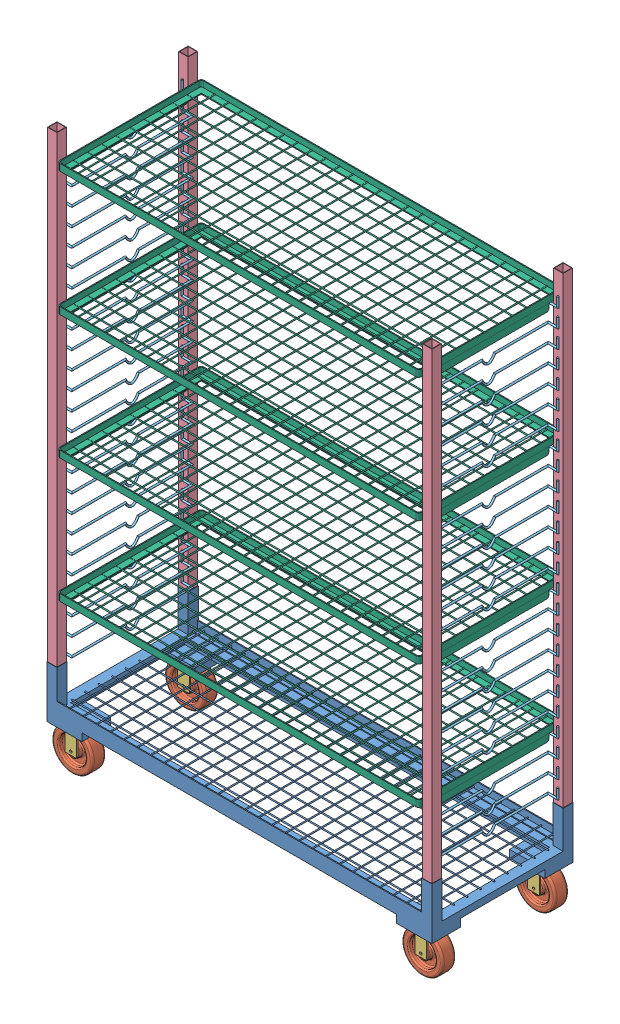
SolidWorks assembly cart_assembly, configuration Default. Lengths in mm.
Overall size (1465.58 2082.8 540.51).
71 component instances, 6 part files, 15 mates.
Components (placement in the parent):
- base-1: base [Default] at (534.0064 765.885 1057.2347) size (1444.62 194.06 530.22)
- wheel_assembly-1: wheel_assembly [Default] at (8.6921 764.7646 844.3099) x (0 0 -1) z (-1 0 0) size (99.57 177.8 152.4)
  - wheel-1: wheel [Default] at (-26.5523 104.0356 130.9582) size (50.8 152.4 152.4)
  - wheel_housing-1: wheel_housing [Default] at (48.6317 2.4356 193.4422) x (0 1 0) z (0 0 1) size (114.3 99.57 124.97)
- wheel_assembly-2: wheel_assembly [Default] at (1321.8721 764.7646 844.3099) x (0 0 -1) z (-1 0 0) size (99.57 177.8 152.4)
  - wheel-1: wheel [Default] at (-26.5523 104.0356 130.9582) size (50.8 152.4 152.4)
  - wheel_housing-1: wheel_housing [Default] at (48.6317 2.4356 193.4422) x (0 1 0) z (0 0 1) size (114.3 99.57 124.97)
- wheel_assembly-3: wheel_assembly [Default] at (8.6921 764.7646 1267.2199) x (0 0 -1) z (-1 0 0) size (99.57 177.8 152.4)
  - wheel-1: wheel [Default] at (-26.5523 104.0356 130.9582) size (50.8 152.4 152.4)
  - wheel_housing-1: wheel_housing [Default] at (48.6317 2.4356 193.4422) x (0 1 0) z (0 0 1) size (114.3 99.57 124.97)
- wheel_assembly-4: wheel_assembly [Default] at (1321.8721 764.7646 1267.2199) x (0 0 -1) z (-1 0 0) size (99.57 177.8 152.4)
  - wheel-1: wheel [Default] at (-26.5523 104.0356 130.9582) size (50.8 152.4 152.4)
  - wheel_housing-1: wheel_housing [Default] at (48.6317 2.4356 193.4422) x (0 1 0) z (0 0 1) size (114.3 99.57 124.97)
- side_assembly-1: side_assembly [Default] at (3135.9189 1569.601 1280.3971) x (0 0 1) z (-1 0 0) size (527.68 1898.65 55.7)
  - side-1: side [Default] at (-485.354 -800.922 1914.779) size (527.68 1898.65 35.56)
  - cross_bar-2: cross_bar [Default] at (-448.2065 -580.3312 1897.771) size (456.56 60.39 42.04)
  - cross_bar-3: cross_bar [Default] at (-448.2065 -513.7832 1897.771) size (456.56 60.39 42.04)
  - cross_bar-4: cross_bar [Default] at (-448.2065 -447.2352 1897.771) size (456.56 60.39 42.04)
  - cross_bar-5: cross_bar [Default] at (-448.2065 -380.6872 1897.771) size (456.56 60.39 42.04)
  - cross_bar-6: cross_bar [Default] at (-448.2065 -314.1392 1897.771) size (456.56 60.39 42.04)
  - cross_bar-7: cross_bar [Default] at (-448.2065 -247.5912 1897.771) size (456.56 60.39 42.04)
  - cross_bar-8: cross_bar [Default] at (-448.2065 -181.0432 1897.771) size (456.56 60.39 42.04)
  - cross_bar-9: cross_bar [Default] at (-448.2065 -114.4952 1897.771) size (456.56 60.39 42.04)
  - cross_bar-10: cross_bar [Default] at (-448.2065 -47.9472 1897.771) size (456.56 60.39 42.04)
  - cross_bar-11: cross_bar [Default] at (-448.2065 18.6008 1897.771) size (456.56 60.39 42.04)
  - cross_bar-12: cross_bar [Default] at (-448.2065 85.1488 1897.771) size (456.56 60.39 42.04)
  - cross_bar-13: cross_bar [Default] at (-448.2065 151.6968 1897.771) size (456.56 60.39 42.04)
  - cross_bar-14: cross_bar [Default] at (-448.2065 218.2448 1897.771) size (456.56 60.39 42.04)
  - cross_bar-15: cross_bar [Default] at (-448.2065 284.7928 1897.771) size (456.56 60.39 42.04)
  - cross_bar-16: cross_bar [Default] at (-448.2065 351.3408 1897.771) size (456.56 60.39 42.04)
  - cross_bar-17: cross_bar [Default] at (-448.2065 417.8888 1897.771) size (456.56 60.39 42.04)
  - cross_bar-18: cross_bar [Default] at (-448.2065 484.4368 1897.771) size (456.56 60.39 42.04)
  - cross_bar-19: cross_bar [Default] at (-448.2065 550.9848 1897.771) size (456.56 60.39 42.04)
  - cross_bar-20: cross_bar [Default] at (-448.2065 617.5328 1897.771) size (456.56 60.39 42.04)
  - cross_bar-21: cross_bar [Default] at (-448.2065 684.0808 1897.771) size (456.56 60.39 42.04)
  - cross_bar-22: cross_bar [Default] at (-448.2065 750.6288 1897.771) size (456.56 60.39 42.04)
  - cross_bar-23: cross_bar [Default] at (-448.2065 817.1768 1897.771) size (456.56 60.39 42.04)
  - cross_bar-24: cross_bar [Default] at (-448.2065 883.7248 1897.771) size (456.56 60.39 42.04)
  - cross_bar-25: cross_bar [Default] at (-448.2065 950.2728 1897.771) size (456.56 60.39 42.04)
  - cross_bar-26: cross_bar [Default] at (-448.2065 1016.8208 1897.771) size (456.56 60.39 42.04)
- side_assembly-2: side_assembly [Default] at (-2067.9061 1569.601 834.0722) x (0 0 -1) z (1 0 0) size (527.68 1898.65 55.7)
  - side-1: side [Default] at (-485.354 -800.922 1914.779) size (527.68 1898.65 35.56)
  - cross_bar-2: cross_bar [Default] at (-448.2065 -580.3312 1897.771) size (456.56 60.39 42.04)
  - cross_bar-3: cross_bar [Default] at (-448.2065 -513.7832 1897.771) size (456.56 60.39 42.04)
  - cross_bar-4: cross_bar [Default] at (-448.2065 -447.2352 1897.771) size (456.56 60.39 42.04)
  - cross_bar-5: cross_bar [Default] at (-448.2065 -380.6872 1897.771) size (456.56 60.39 42.04)
  - cross_bar-6: cross_bar [Default] at (-448.2065 -314.1392 1897.771) size (456.56 60.39 42.04)
  - cross_bar-7: cross_bar [Default] at (-448.2065 -247.5912 1897.771) size (456.56 60.39 42.04)
  - cross_bar-8: cross_bar [Default] at (-448.2065 -181.0432 1897.771) size (456.56 60.39 42.04)
  - cross_bar-9: cross_bar [Default] at (-448.2065 -114.4952 1897.771) size (456.56 60.39 42.04)
  - cross_bar-10: cross_bar [Default] at (-448.2065 -47.9472 1897.771) size (456.56 60.39 42.04)
  - cross_bar-11: cross_bar [Default] at (-448.2065 18.6008 1897.771) size (456.56 60.39 42.04)
  - cross_bar-12: cross_bar [Default] at (-448.2065 85.1488 1897.771) size (456.56 60.39 42.04)
  - cross_bar-13: cross_bar [Default] at (-448.2065 151.6968 1897.771) size (456.56 60.39 42.04)
  - cross_bar-14: cross_bar [Default] at (-448.2065 218.2448 1897.771) size (456.56 60.39 42.04)
  - cross_bar-15: cross_bar [Default] at (-448.2065 284.7928 1897.771) size (456.56 60.39 42.04)
  - cross_bar-16: cross_bar [Default] at (-448.2065 351.3408 1897.771) size (456.56 60.39 42.04)
  - cross_bar-17: cross_bar [Default] at (-448.2065 417.8888 1897.771) size (456.56 60.39 42.04)
  - cross_bar-18: cross_bar [Default] at (-448.2065 484.4368 1897.771) size (456.56 60.39 42.04)
  - cross_bar-19: cross_bar [Default] at (-448.2065 550.9848 1897.771) size (456.56 60.39 42.04)
  - cross_bar-20: cross_bar [Default] at (-448.2065 617.5328 1897.771) size (456.56 60.39 42.04)
  - cross_bar-21: cross_bar [Default] at (-448.2065 684.0808 1897.771) size (456.56 60.39 42.04)
  - cross_bar-22: cross_bar [Default] at (-448.2065 750.6288 1897.771) size (456.56 60.39 42.04)
  - cross_bar-23: cross_bar [Default] at (-448.2065 817.1768 1897.771) size (456.56 60.39 42.04)
  - cross_bar-24: cross_bar [Default] at (-448.2065 883.7248 1897.771) size (456.56 60.39 42.04)
  - cross_bar-25: cross_bar [Default] at (-448.2065 950.2728 1897.771) size (456.56 60.39 42.04)
  - cross_bar-26: cross_bar [Default] at (-448.2065 1016.8208 1897.771) size (456.56 60.39 42.04)
- shelf-1: shelf [Default] at (534.0064 1160.1482 1057.1077) size (1356.49 50.8 540.51)
- shelf-2: shelf [Default] at (534.0064 1625.9842 1057.1077) size (1356.49 50.8 540.51)
- shelf-3: shelf [Default] at (534.0064 2091.8202 1057.1077) size (1356.49 50.8 540.51)
- shelf-4: shelf [Default] at (534.0064 2557.6562 1057.1077) size (1356.49 50.8 540.51)
Mates (geometry in assembly coordinates):
- Coincident1: coincident: plane of base-1 through (534.0064 762.329 1057.2347) normal (0 -1 0); plane of ? through (-184.7501 762.329 1219.2232) normal (0 1 0)
- Coincident2: coincident anti-aligned: plane of base-1 through (-59.7821 736.929 1318.7912) normal (-1 0 0); plane of ? through (-59.7821 755.979 1219.2232) normal (1 0 0)
- Coincident3: coincident anti-aligned: plane of base-1 through (-184.7501 736.929 1219.2232) normal (0 0 1); plane of ? through (-184.7501 755.979 1219.2232) normal (0 0 -1)
- Coincident4: coincident anti-aligned: plane of base-1 through (534.0064 762.329 1057.2347) normal (0 -1 0); plane of wheel_assembly-1/wheel_housing-1 through (-184.7501 762.329 795.6782) normal (0 1 0)
- Coincident5: coincident anti-aligned: plane of base-1 through (-184.7501 736.929 795.6782) normal (1 0 0); plane of wheel_assembly-1/wheel_housing-1 through (-184.7501 755.979 795.6782) normal (-1 0 0)
- Coincident6: coincident anti-aligned: plane of base-1 through (-184.7501 736.929 895.2462) normal (0 0 -1); plane of wheel_assembly-1/wheel_housing-1 through (-184.7501 755.979 895.2462) normal (0 0 1)
- Coincident7: coincident anti-aligned: plane of base-1 through (1255.0489 930.985 793.3922) normal (-1 0 0); plane of side_assembly-1/side-1 through (1255.0489 2667.329 793.3922) normal (1 0 0)
- Coincident8: coincident anti-aligned: plane of base-1 through (1255.0489 930.985 793.3922) normal (0 0 1); plane of side_assembly-1/side-1 through (1219.4889 2667.329 793.3922) normal (0 0 -1)
- Coincident10: coincident anti-aligned: plane of base-1 through (534.0064 768.679 1057.2347) normal (0 1 0); plane of side_assembly-1/side-1 through (1221.1399 768.679 795.0432) normal (0 -1 0)
- Coincident11: coincident anti-aligned: plane of base-1 through (-187.0361 930.985 793.3922) normal (0 0 1); plane of side_assembly-2/side-1 through (-151.4761 2667.329 793.3922) normal (0 0 -1)
- Coincident12: coincident anti-aligned: plane of base-1 through (-187.0361 930.985 793.3922) normal (1 0 0); plane of side_assembly-2/side-1 through (-187.0361 2667.329 828.9522) normal (-1 0 0)
- Coincident13: coincident anti-aligned: plane of base-1 through (534.0064 768.679 1057.2347) normal (0 1 0); plane of side_assembly-2/side-1 through (-153.1271 768.679 1319.4262) normal (0 -1 0)
- Distance1: distance = 7.239 mm anti-aligned: plane of shelf-1 through (-144.2371 1181.9922 1316.1877) normal (-1 0 0); plane of side_assembly-2/side-1 through (-151.4761 2667.329 1321.0772) normal (1 0 0)
- Tangent1: tangent anti-aligned: cylinder of side_assembly-2/cross_bar-5 through (-134.575 1153.3537 1035.2948) axis (0 0 -1) radius 3.2385; plane of shelf-1 through (1201.0739 1156.5922 1316.1877) normal (0 -1 0)
- Distance2: distance = 6.2865 mm aligned: plane of shelf-1 through (-133.0611 1181.9922 1327.3637) normal (0 0 1); plane of side_assembly-1/side-1 through (1219.4889 2667.329 1321.0772) normal (0 0 1)
